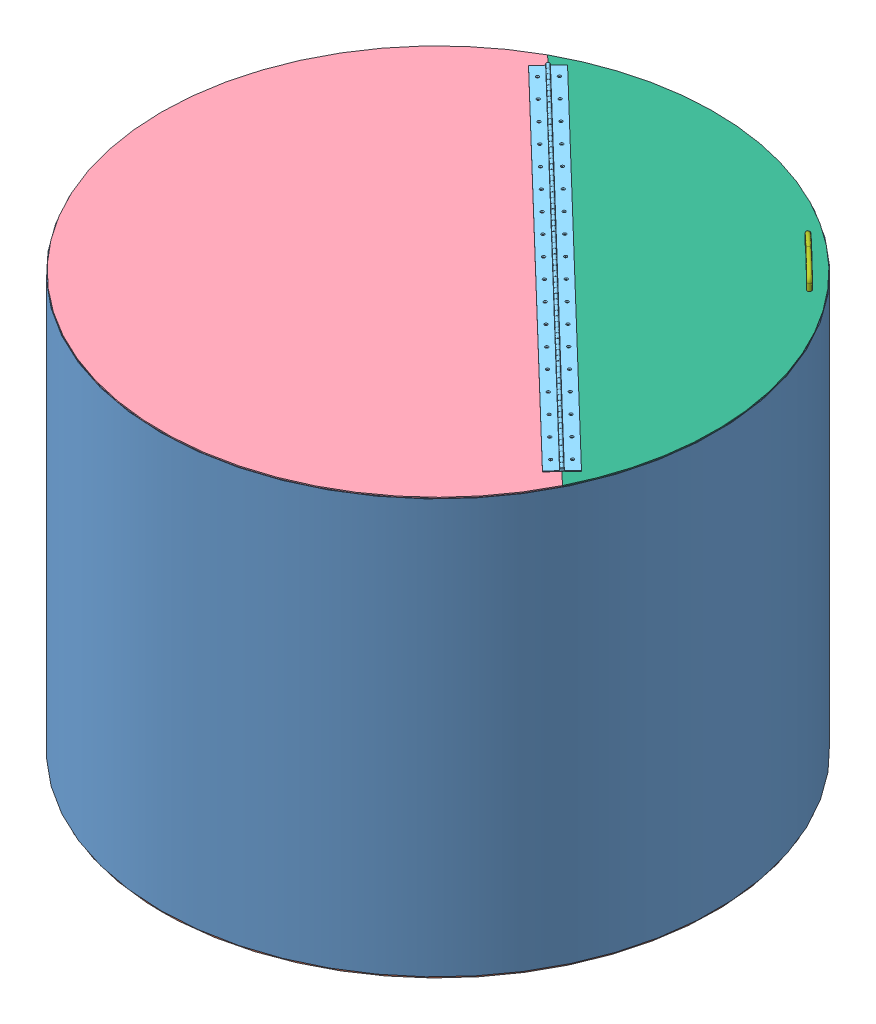
SolidWorks assembly Barley chamber assembly, configuration Default. Lengths in mm.
Overall size (1422.52 800.79 1423.18).
7 component instances, 7 part files, 15 mates.
Components (placement in the parent):
- barley chamber outer tube-1: barley chamber outer tube [Default] at (-10.4168 -173.6473 123.4702) size (1019.97 762 1019.97)
- bottom of barley chamber-1: bottom of barley chamber [Default] at (-10.4168 -176.8223 123.4702) size (1016 720.03 1016)
- wheel track-1: wheel track [Default] at (-10.4168 435.9527 123.4702) size (1009.65 3.17 1009.65)
- welded lid-1: welded lid [Default] at (-10.4168 588.3527 123.4702) x (-0.720995 0 -0.69294) z (0.69294 0 -0.720995) size (1017.98 1.98 661.39)
- lid hinge-1: lid hinge [1658A7] at (92.9958 591.0985 11.4844) x (0.69294 0 -0.720995) z (0.720995 0 0.69294) size (50.8 6.22 914.4)
- opening lid-1: opening lid [Default] at (-10.4168 590.3365 123.4702) x (-0.720995 0 -0.69294) z (0 -1 0) size (971.28 356.59 1.98)
- handle-1: handle [Default] at (323.9959 590.3365 -224.4822) x (0.720995 0 0.69294) z (-0.69294 0 0.720995) size (110.13 33.63 8.83)
Mates (geometry in assembly coordinates):
- Coincident1: coincident anti-aligned: plane of barley chamber outer tube-1 through (-10.4168 -173.6473 123.4702) normal (0 -1 0); plane of bottom of barley chamber-1 through (-10.4168 -173.6473 123.4702) normal (0 1 0)
- Concentric1: concentric aligned: circle of barley chamber outer tube-1; circle of bottom of barley chamber-1
- Concentric2: concentric aligned: circle of barley chamber outer tube-1; circle of wheel track-1
- Distance1: distance = 609.6 mm anti-aligned: plane of wheel track-1 through (-10.4168 435.9527 123.4702) normal (0 -1 0); plane of bottom of barley chamber-1 through (-10.4168 -173.6473 123.4702) normal (0 1 0)
- Coincident3: coincident anti-aligned: plane of barley chamber outer tube-1 through (-10.4168 588.3527 123.4702) normal (0 1 0); plane of welded lid-1 through (-10.4168 588.3527 123.4702) normal (0 -1 0)
- Parallel1: parallel aligned: line of welded lid-1 through (445.331 590.3365 350.1094) axis (-0.720995 0 -0.69294); line of lid hinge-1 through (440.2355 591.8605 309.9832) axis (-0.720995 0 -0.69294)
- Distance2: distance = 1.524 mm aligned: plane of lid hinge-1 through (405.0342 591.8605 346.6097) normal (0 1 0); plane of welded lid-1 through (-10.4168 590.3365 123.4702) normal (0 1 0)
- Distance3: distance = 1.524 mm aligned: plane of opening lid-1 through (-10.4168 590.3365 123.4702) normal (0 1 0); plane of lid hinge-1 through (405.0342 591.8605 346.6097) normal (0 1 0)
- Concentric7: concentric aligned: circle of welded lid-1; circle of lid hinge-1
- Concentric8: concentric anti-aligned: circle of lid hinge-1; circle of opening lid-1
- Coincident5: coincident anti-aligned: plane of opening lid-1 through (-10.4168 590.3365 123.4702) normal (0 1 0); plane of handle-1 through (360.6225 590.3365 -189.2808) normal (0 -1 0)
- Concentric9: concentric anti-aligned: circle of opening lid-1; circle of handle-1
- Concentric10: concentric aligned: circle of opening lid-1; circle of handle-1
- Concentric11: concentric aligned: circle of barley chamber outer tube-1; circle of welded lid-1
- Concentric12: concentric anti-aligned: circle of lid hinge-1; circle of opening lid-1
